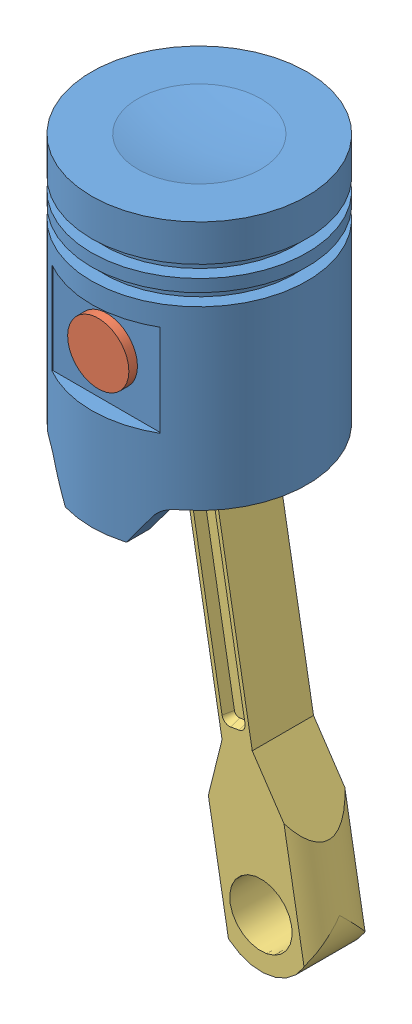
SolidWorks assembly Piston.Pin.ConnectingRod, configuration Default. Lengths in mm.
Overall size (51.73 140.79 44.7).
3 component instances, 3 part files, 3 mates.
Components (placement in the parent):
- Main Piston Part-1: Main Piston Part [Default] at (16.44 4.5855 46.4214) size (44.7 59.44 44.7)
- Piston-1: Piston [Default] at (16.44 35.0655 25.4664) x (0.984859 0.173355 0) z (0 0 1) size (12.7 12.7 41.91)
- connecting rod-1: connecting rod [Default] at (34.0529 -64.9963 38.5569) x (0.984859 0.173355 0) z (0 0 1) size (20.32 121.92 12.7)
Mates (geometry in assembly coordinates):
- Width3: width aligned: plane of Piston-1 through (16.44 35.0655 67.3764) normal (0 0 1); plane of Piston-1 through (16.44 35.0655 25.4664) normal (0 0 -1); plane of Main Piston Part-1 through (16.44 4.5855 65.5984) normal (0 0 1); plane of Main Piston Part-1 through (16.44 4.5855 27.2444) normal (0 0 -1)
- Concentric6: concentric anti-aligned: cylinder of Main Piston Part-1 through (16.44 35.0655 24.0694) axis (0 0 1) radius 6.35; cylinder of Piston-1 through (16.44 35.0655 67.3764) axis (0 0 -1) radius 6.35
- Lock1: lock: unknown of Piston-1; unknown of connecting rod-1
